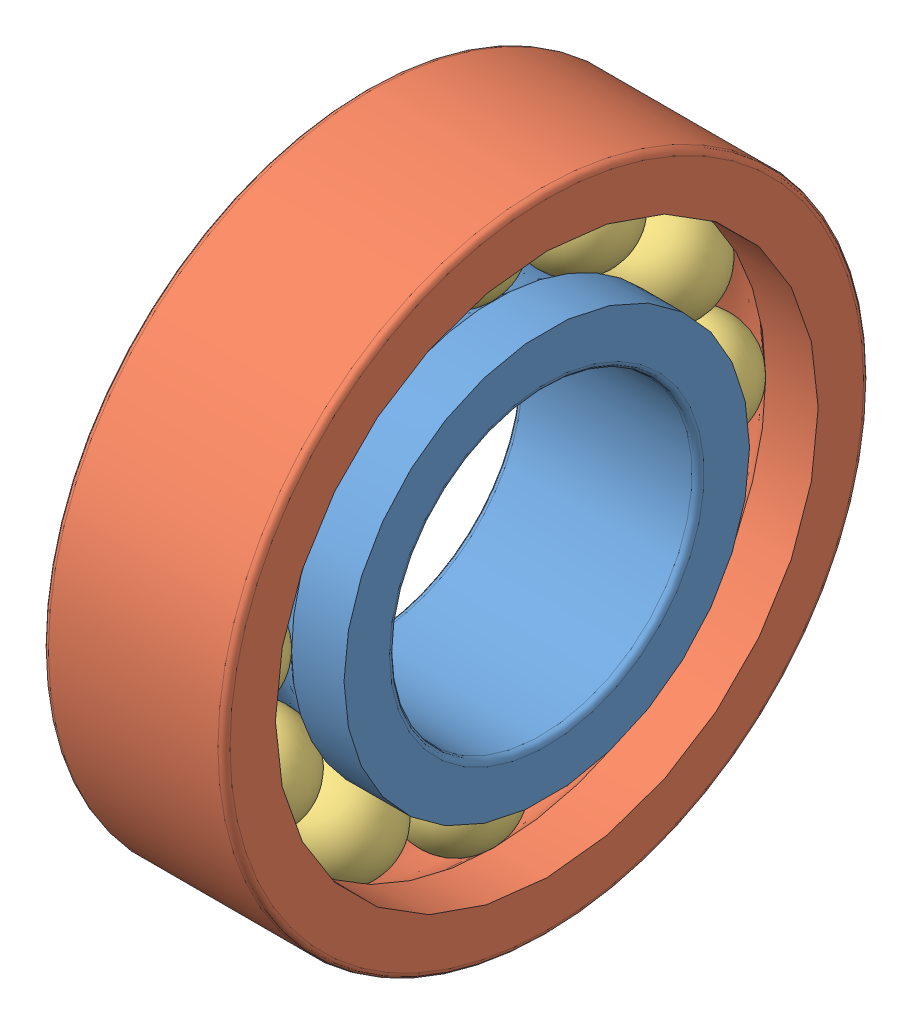
SolidWorks assembly Roulement 6002, configuration Défaut. Lengths in mm.
Overall size (9 32 32).
14 component instances, 3 part files, 4 mates.
Components (placement in the parent):
- Roulement_r1rb_Bint33-1: Roulement_r1rb_Bint33 [Défaut] at origin size (9 20.1 20.1)
- Roulement_r1rb_Bext33-1: Roulement_r1rb_Bext33 [Défaut] at origin size (9 32 32)
- Roulement_r1rb_Eroul33-1: Roulement_r1rb_Eroul33 [Défaut] at (0.3 0 -7.8) size (5.1 5.1 5.1)
- Roulement_r1rb_Eroul33-2: Roulement_r1rb_Eroul33 [Défaut] at (0.3 3.9 -6.755) x (1 0 0) z (0 -0.5 0.866025) size (5.1 5.1 5.1)
- Roulement_r1rb_Eroul33-3: Roulement_r1rb_Eroul33 [Défaut] at (0.3 6.755 -3.9) x (1 0 0) z (0 -0.866025 0.5) size (5.1 5.1 5.1)
- Roulement_r1rb_Eroul33-4: Roulement_r1rb_Eroul33 [Défaut] at (0.3 7.8 0) x (1 0 0) z (0 -1 0) size (5.1 5.1 5.1)
- Roulement_r1rb_Eroul33-5: Roulement_r1rb_Eroul33 [Défaut] at (0.3 6.755 3.9) x (1 0 0) z (0 -0.866025 -0.5) size (5.1 5.1 5.1)
- Roulement_r1rb_Eroul33-6: Roulement_r1rb_Eroul33 [Défaut] at (0.3 3.9 6.755) x (1 0 0) z (0 -0.5 -0.866025) size (5.1 5.1 5.1)
- Roulement_r1rb_Eroul33-7: Roulement_r1rb_Eroul33 [Défaut] at (0.3 0 7.8) x (1 0 0) z (0 0 -1) size (5.1 5.1 5.1)
- Roulement_r1rb_Eroul33-8: Roulement_r1rb_Eroul33 [Défaut] at (0.3 -3.9 6.755) x (1 0 0) z (0 0.5 -0.866025) size (5.1 5.1 5.1)
- Roulement_r1rb_Eroul33-9: Roulement_r1rb_Eroul33 [Défaut] at (0.3 -6.755 3.9) x (1 0 0) z (0 0.866025 -0.5) size (5.1 5.1 5.1)
- Roulement_r1rb_Eroul33-10: Roulement_r1rb_Eroul33 [Défaut] at (0.3 -7.8 0) x (1 0 0) z (0 1 0) size (5.1 5.1 5.1)
- Roulement_r1rb_Eroul33-11: Roulement_r1rb_Eroul33 [Défaut] at (0.3 -6.755 -3.9) x (1 0 0) z (0 0.866025 0.5) size (5.1 5.1 5.1)
- Roulement_r1rb_Eroul33-12: Roulement_r1rb_Eroul33 [Défaut] at (0.3 -3.9 -6.755) x (1 0 0) z (0 0.5 0.866025) size (5.1 5.1 5.1)
Mates (geometry in assembly coordinates):
- Coïncidente1: coincident: point of ?
- Coïncidente2: coincident: unknown of ?
- Coïncidente4: coincident: point of Roulement_r1rb_Eroul33-1; point of assembly
- Parallèle1: parallel aligned: plane of Roulement_r1rb_Bint33-1 through (0 0 0) normal (1 0 0); plane of Roulement_r1rb_Bext33-1 through (0 0 0) normal (1 0 0)
